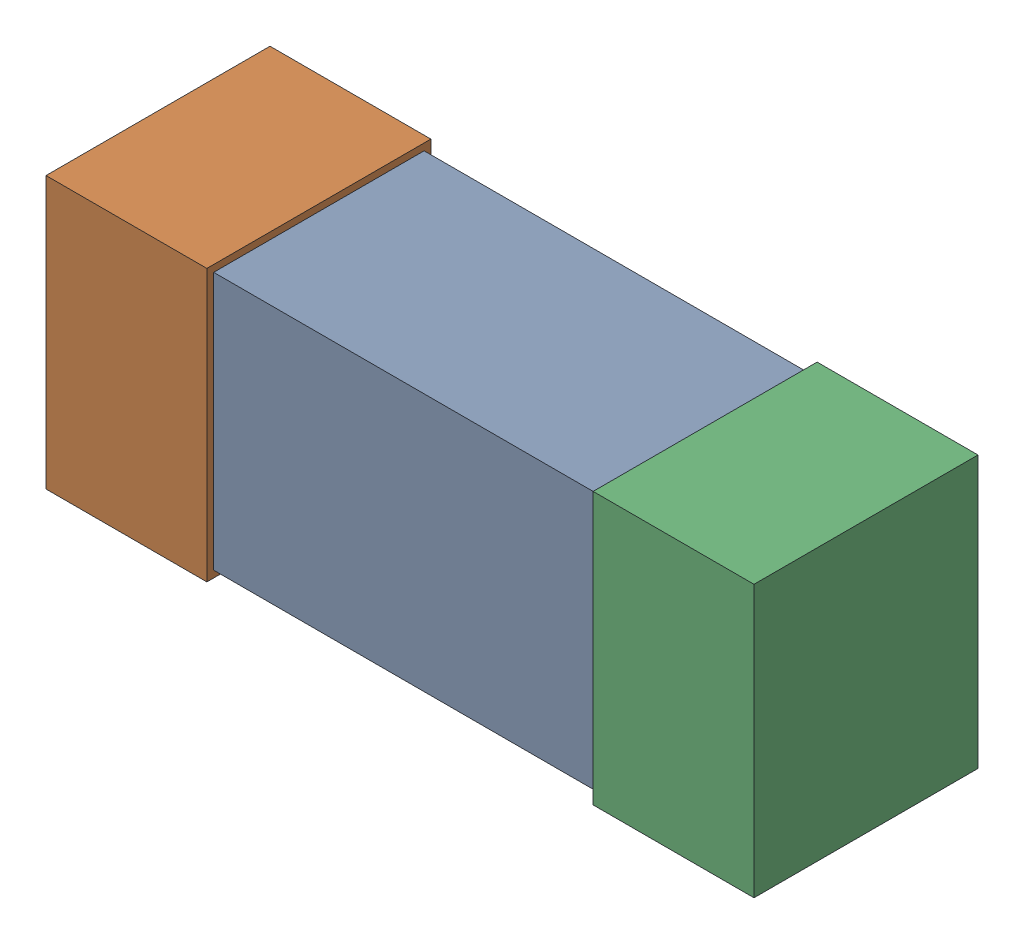
SolidWorks assembly C1, configuration Default. Lengths in mm.
Overall size (1.04 0.4 0.33).
4 component instances, 3 part files, 0 mates.
Components (placement in the parent):
- Open CASCADE STEP translator 6.8 1.3.1-1: Open CASCADE STEP translator 6.8 1.3.1 [Default] at origin size (1.04 0.4 0.33)
  - Body_1_3-1: Body_1_3 [Default] at origin size (0.73 0.38 0.31)
  - Pin_1-1: Pin_1 [Default] at origin size (0.24 0.4 0.33)
  - Pin_2-1: Pin_2 [Default] at (1.506 0 0) x (-1 0 0) z (0 0 1) size (0.24 0.4 0.33)
